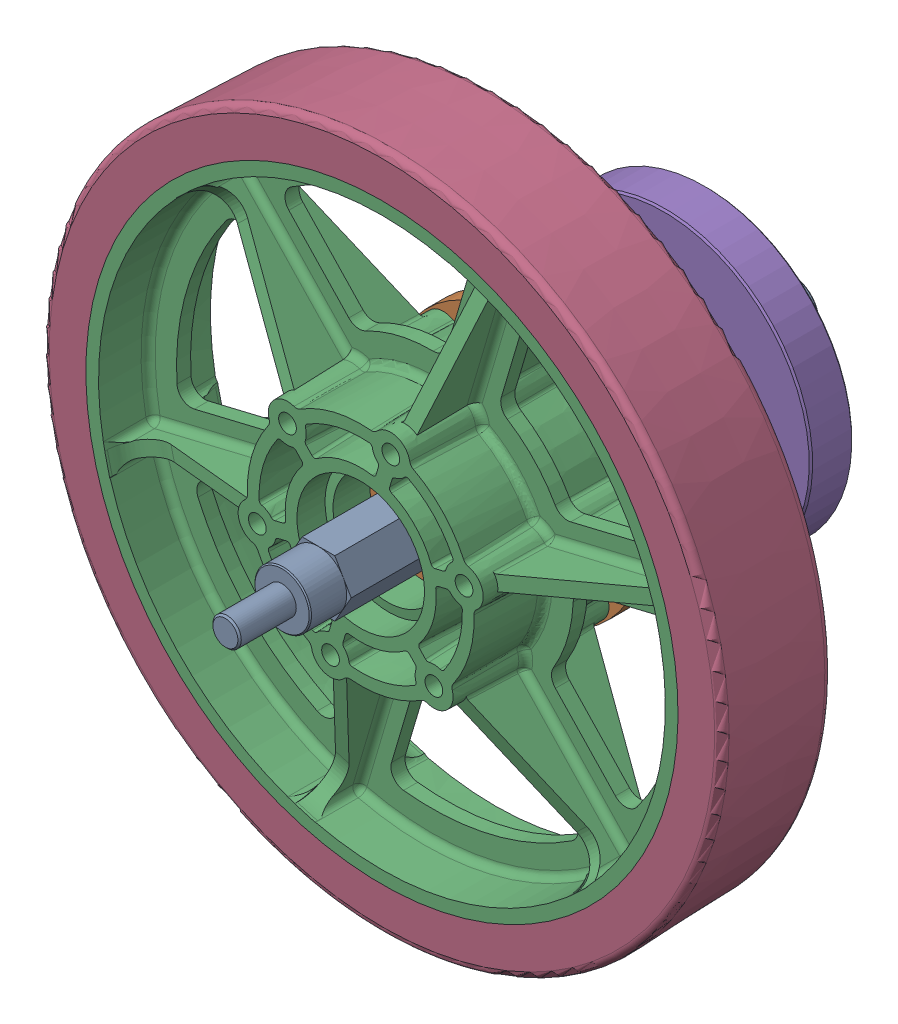
SolidWorks assembly ws_drive_axle_wheel_asm_revc, configuration Default. Lengths in mm.
Overall size (215.3 215.3 126.9).
8 component instances, 6 part files, 0 mates.
Components (placement in the parent):
- ws_wheel_shaft_revc-1: ws_wheel_shaft_revc [Default] at origin size (14.66 12.7 126.9)
- 500-hex-hub-1: 500-hex-hub [Default] at (0.044 0.0254 66.464) x (0 0 1) z (-0.866025 0.5 0) size (25.4 57.15 57.15)
- 2008-FIRST-Wheel-1: 2008-FIRST-Wheel [Default] at (0.044 0.0254 83.7184) x (0.688652 -0.725092 0) z (0 0 -1) size (152.29 152.29 35.19)
  - Hub-1: Hub [Default] at origin size (139.7 139.7 35.19)
  - Tread-1: Tread [Default] at origin size (152.29 152.29 25.41)
- 50t_ws_output_gear_revb-1: 50t_ws_output_gear_revb [Default] at (185.5309 107.1163 858.0866) x (0 0 -1) z (-0.5 0.866025 0) size (10.86 66.04 66.04)
- snap_ring_97633A200-1: snap_ring_97633A200 [Default] at (0 0 74.9173) x (0 0 1) z (-1 0 0) size (0.89 16.1 14.34)
- snap_ring_97633A200-2: snap_ring_97633A200 [Default] at (0 0 48.1711) x (0 0 -1) z (1 0 0) size (0.89 16.1 14.34)
